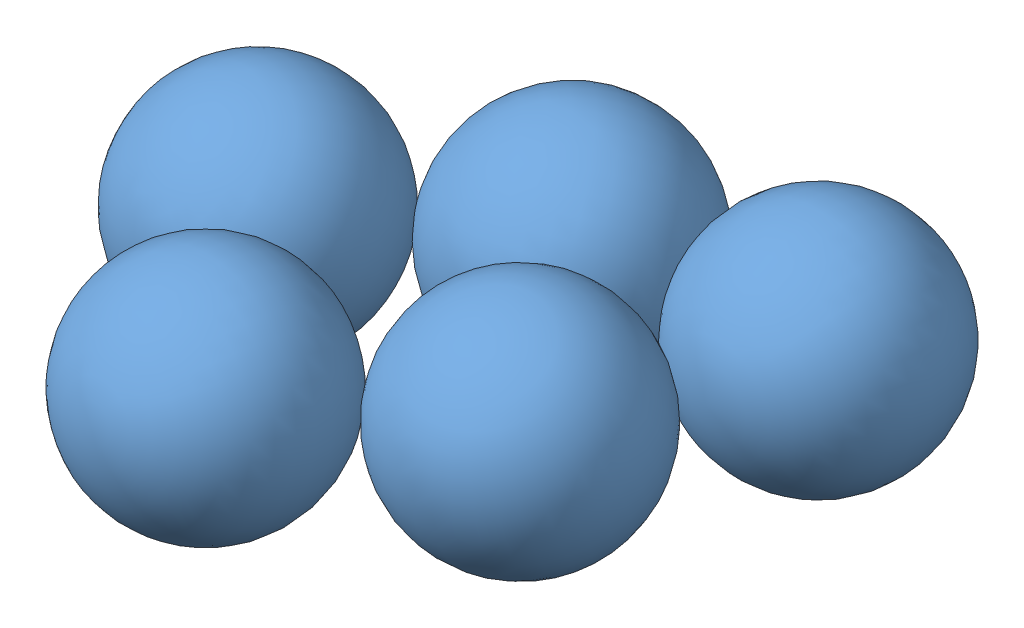
SolidWorks assembly power_tank, configuration Default. Lengths in mm.
Overall size (1560.46 846.95 1367.46).
5 component instances, 1 part files, 11 mates.
Components (placement in the parent):
- power_tank_10-1: power_tank_10 [Default] at (-67.1815 281.3265 414.5148) size (500 500 500)
- power_tank_10-2: power_tank_10 [Default] at (-251.8267 476.4977 723.0274) x (0.786037 -0.315714 0.53148) z (0.083274 0.905991 0.415025) size (500 500 500)
- power_tank_10-3: power_tank_10 [Default] at (-733.4982 325.3571 380.2859) x (0.665484 -0.133715 0.734337) z (-0.678573 0.301428 0.669836) size (500 500 500)
- power_tank_10-4: power_tank_10 [Default] at (-1034.3616 424.6302 664.9742) x (0.724325 0.588989 -0.358392) z (-0.233278 0.698521 0.676499) size (500 500 500)
- power_tank_10-5: power_tank_10 [Default] at (-695.3433 297.5492 1147.5051) x (0.994968 0.097333 0.023775) z (-0.042044 0.190197 0.980845) size (500 500 500)
Mates (geometry in assembly coordinates):
- Tangent2: tangent anti-aligned: sphere of power_tank_10-1; sphere of power_tank_10-2
- Tangent3: tangent anti-aligned: sphere of power_tank_10-1; sphere of power_tank_10-3
- Tangent4: tangent anti-aligned: sphere of power_tank_10-2; sphere of power_tank_10-3
- Tangent5: tangent anti-aligned: sphere of power_tank_10-2; sphere of power_tank_10-5
- Tangent7: tangent anti-aligned: sphere of power_tank_10-3; sphere of power_tank_10-4
- Tangent9: tangent anti-aligned: sphere of power_tank_10-4; sphere of power_tank_10-5
- Tangent10: tangent anti-aligned: unknown of ?
- Tangent11: tangent anti-aligned: unknown of ?
- Tangent12: tangent anti-aligned: unknown of ?
- Tangent13: tangent anti-aligned: unknown of ?
- Distance1: distance = 200 mm anti-aligned: sphere of power_tank_10-3; sphere of power_tank_10-5
